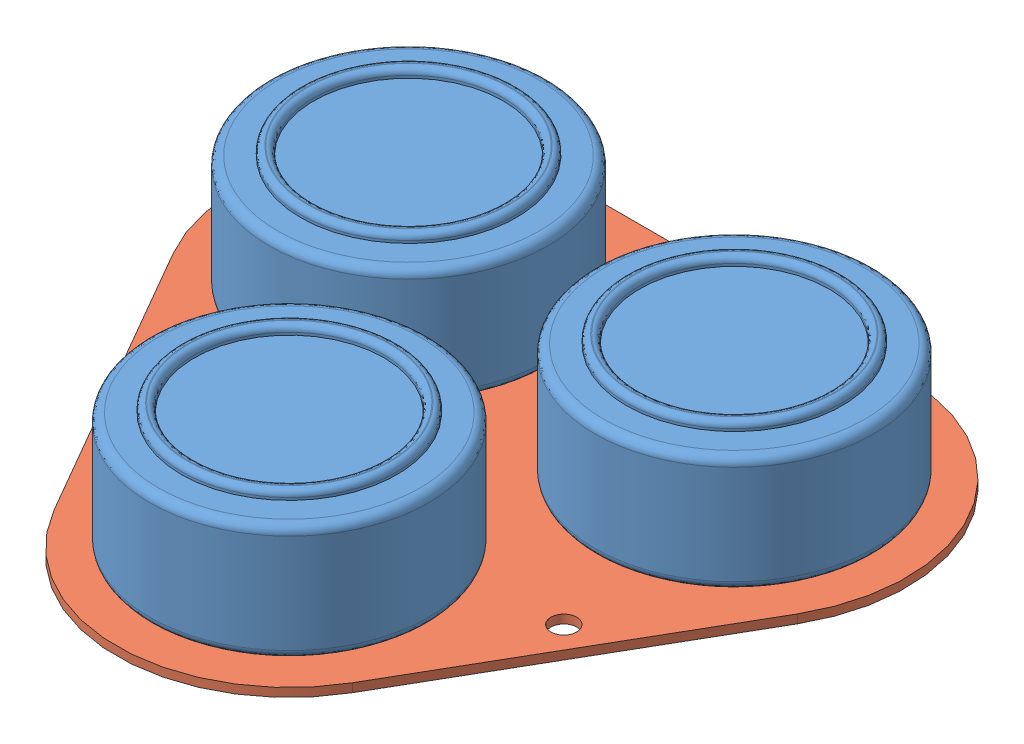
SolidWorks assembly Alphasense, configuration Default. Lengths in mm.
Overall size (77.81 19.5 72.74).
4 component instances, 2 part files, 8 mates.
Components (placement in the parent):
- Alphasense-1: Alphasense [Default] at origin size (32.33 14.5 32.33)
- Alphasense-2: Alphasense [Default] at (37.807 0 0) size (32.33 14.5 32.33)
- Alphasense-3: Alphasense [Default] at (18.9035 0 32.7418) size (32.33 14.5 32.33)
- AlphasenseBoard-1: AlphasenseBoard [Default] at (18.9035 -1 10.9139) size (77.81 5 72.74)
Mates (geometry in assembly coordinates):
- Parallel1: parallel aligned: plane of Alphasense-1 through (0 13.5 0) normal (0 1 0); plane of Alphasense-2 through (37.807 13.5 0) normal (0 1 0)
- Parallel2: parallel aligned: plane of Alphasense-1 through (0 13.5 0) normal (0 1 0); plane of Alphasense-2 through (37.807 13.5 0) normal (0 1 0)
- Coincident1: coincident aligned: plane of Alphasense-1 through (0 13.5 0) normal (0 1 0); plane of Alphasense-2 through (37.807 13.5 0) normal (0 1 0)
- Coincident2: coincident aligned: plane of Alphasense-1 through (0 13.5 0) normal (0 1 0); plane of Alphasense-3 through (18.9035 13.5 32.7418) normal (0 1 0)
- Coincident4: coincident anti-aligned: plane of Alphasense-1 through (0 0 0) normal (0 -1 0); plane of AlphasenseBoard-1 through (0 0 0) normal (0 1 0)
- Concentric1: concentric aligned: cylinder of Alphasense-1 through (0 13.5 0) axis (0 -1 0) radius 16.1655; cylinder of AlphasenseBoard-1 through (0 0 0) axis (0 -1 0) radius 2
- Concentric2: concentric aligned: cylinder of Alphasense-2 through (37.807 13.5 0) axis (0 -1 0) radius 16.1655; cylinder of AlphasenseBoard-1 through (37.807 0 0) axis (0 -1 0) radius 2
- Concentric3: concentric aligned: cylinder of Alphasense-3 through (18.9035 13.5 32.7418) axis (0 -1 0) radius 16.1655; cylinder of AlphasenseBoard-1 through (18.9035 0 32.7418) axis (0 -1 0) radius 2
